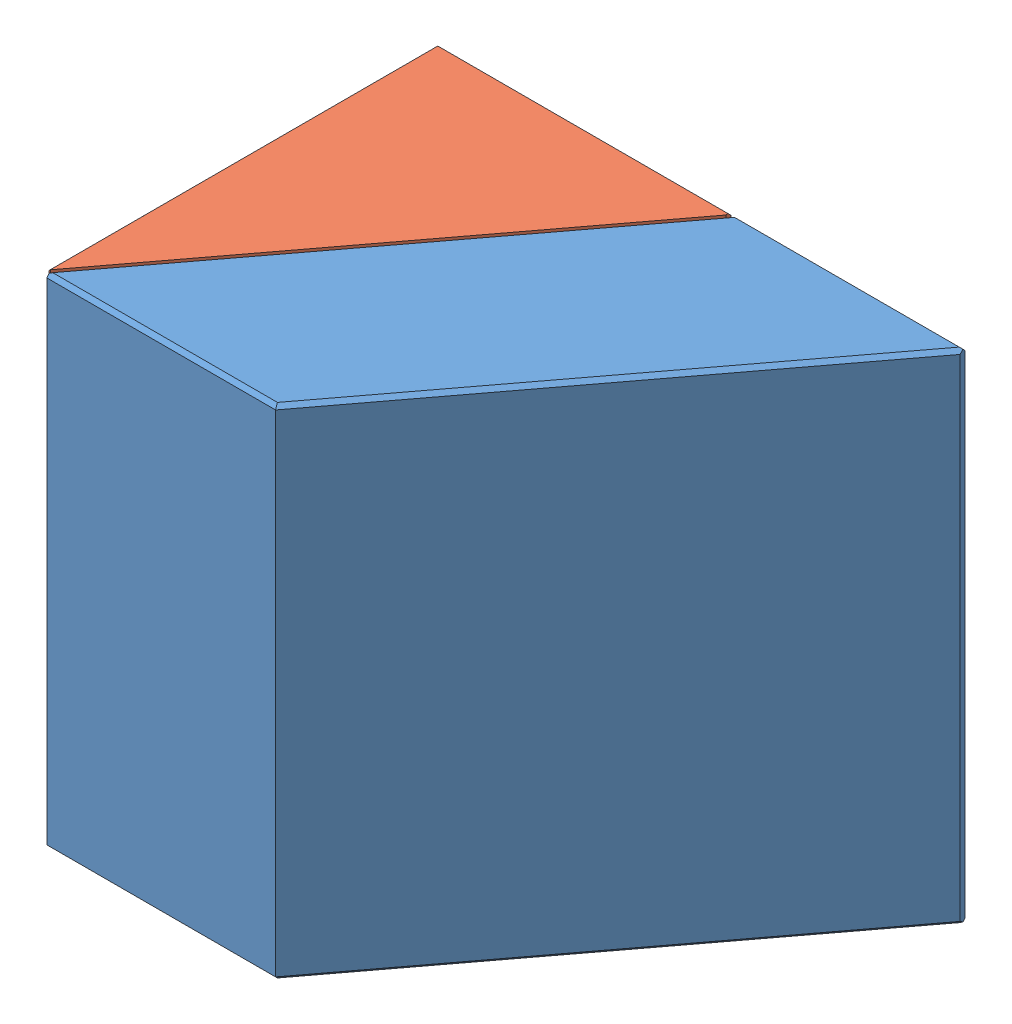
SolidWorks assembly 9510170000040, configuration По умолчанию. Lengths in mm.
Overall size (21.19 20 15.9).
2 component instances, 2 part files, 3 mates.
Components (placement in the parent):
- 9510170000041-1: 9510170000041 [По умолчанию] at (-11.1761 -9.434 0) size (21.01 20 15.9)
- 9510170000042-3: 9510170000042 [По умолчанию] at (-11.1775 -9.434 0.0019) size (11.8 20 15.69)
Mates (geometry in assembly coordinates):
- Совпадение1: coincident anti-aligned: plane of 9510170000041-1 through (-11.1761 10.566 0) normal (-0.798636 0 -0.601815); plane of 9510170000042-3 through (-11.1775 10.566 0.0019) normal (0.798636 0 0.601815)
- Ширина1: width anti-aligned: plane of 9510170000042-3 through (-11.1775 10.566 -15.9) normal (0 1 0); plane of 9510170000042-3 through (-11.1775 -9.434 -15.9) normal (0 -1 0); plane of 9510170000041-1 through (0.8054 -9.434 -15.9) normal (0 -1 0); plane of 9510170000041-1 through (0.8054 10.566 -15.9) normal (0 1 0)
- Совпадение2: coincident aligned: plane of 9510170000041-1 through (0.8054 10.566 -15.9) normal (0 0 -1); line of 9510170000042-3 through (-11.0275 -9.284 -15.9) axis (0 1 0)
